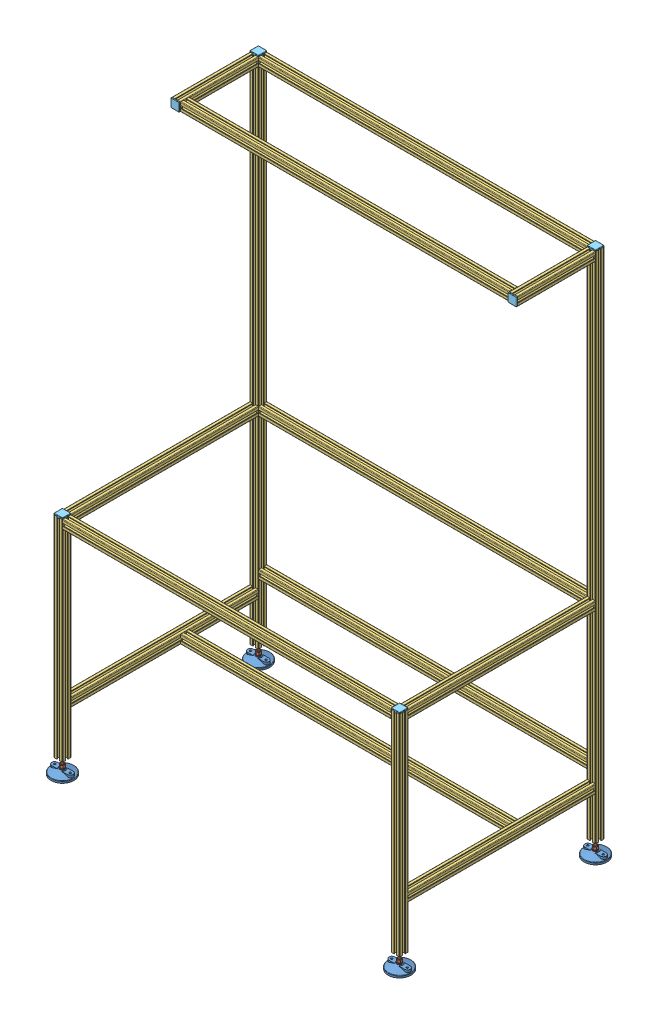
SolidWorks assembly AL-1 Рабочий стол малый, configuration По умолчанию. Lengths in mm.
Overall size (1249 1834.2 759).
56 component instances, 6 part files, 43 mates.
Components (placement in the parent):
- AL-340.010BA.01 Опора D80 с противоскользящей вставкой-8: AL-340.010BA.01 Опора D80 с противоскользящей вставкой [Default] x (0 0 1) z (1 0 0) size (79 18 79)
- AL-1Y12.A42A.01 Шпилька к опоре М8х80-1: AL-1Y12.A42A.01 Шпилька к опоре М8х80 [Default] x (-0.999247 0 -0.038788) z (-0.038788 0 0.999247) size (15 105.5 18.13)
- AL-1-PS-3030.001 Профиль-2: AL-1-PS-3030.001 Профиль [Default] at (0 1765 285) size (30 30 270)
- AL-1-PS-3030.001 Профиль-4: AL-1-PS-3030.001 Профиль [-01] at (0 715 665) size (30 30 650)
- AL-1-PS-3030.001 Профиль-5: AL-1-PS-3030.001 Профиль [-02] at (0 165 665) size (30 30 650)
- AL-1-PS-3030.001 Профиль-3: AL-1-PS-3030.001 Профиль [-03] at (0 0 680) x (1 0 0) z (0 -1 0) size (30 30 730)
- AL-1-PS-3030.001 Профиль-16: AL-1-PS-3030.001 Профиль [-04] at (-1155 1765 270) x (0 0 1) z (-1 0 0) size (30 30 1140)
- AL-1-PS-3030.001 Профиль-11: AL-1-PS-3030.001 Профиль [-04] at (-1155 715 680) x (0 0 1) z (-1 0 0) size (30 30 1140)
- AL-1-PS-3030.001 Профиль-12: AL-1-PS-3030.001 Профиль [-04] at (-1155 715 0) x (0 0 1) z (-1 0 0) size (30 30 1140)
- AL-1-PS-3030.001 Профиль-14: AL-1-PS-3030.001 Профиль [-04] at (-1155 225 0) x (0 0 1) z (-1 0 0) size (30 30 1140)
- AL-1-PS-3030.001 Профиль-15: AL-1-PS-3030.001 Профиль [-04] at (-1155 1765 0) x (0 0 1) z (-1 0 0) size (30 30 1140)
- AL-1-PS-3030.001 Профиль-13: AL-1-PS-3030.001 Профиль [-04] at (-1155 165 270) x (0 0 1) z (-1 0 0) size (30 30 1140)
- AL-1-PS-3030.001 Профиль-1: AL-1-PS-3030.001 Профиль [-05] x (1 0 0) z (0 -1 0) size (30 30 1780)
- AL-340.010BA.01 Опора D80 с противоскользящей вставкой-9: AL-340.010BA.01 Опора D80 с противоскользящей вставкой [Default] at (-1170 0 0) x (0 0 1) z (1 0 0) size (79 18 79)
- AL-340.010BA.01 Опора D80 с противоскользящей вставкой-10: AL-340.010BA.01 Опора D80 с противоскользящей вставкой [Default] at (0 0 680) x (0 0 1) z (1 0 0) size (79 18 79)
- AL-340.010BA.01 Опора D80 с противоскользящей вставкой-11: AL-340.010BA.01 Опора D80 с противоскользящей вставкой [Default] at (-1170 0 680) x (0 0 1) z (1 0 0) size (79 18 79)
- AL-1Y12.A42A.01 Шпилька к опоре М8х80-2: AL-1Y12.A42A.01 Шпилька к опоре М8х80 [Default] at (-1170 0 0) x (-0.999247 0 -0.038788) z (-0.038788 0 0.999247) size (15 105.5 18.13)
- AL-1Y12.A42A.01 Шпилька к опоре М8х80-3: AL-1Y12.A42A.01 Шпилька к опоре М8х80 [Default] at (0 0 680) x (-0.999247 0 -0.038788) z (-0.038788 0 0.999247) size (15 105.5 18.13)
- AL-1Y12.A42A.01 Шпилька к опоре М8х80-4: AL-1Y12.A42A.01 Шпилька к опоре М8х80 [Default] at (-1170 0 680) x (-0.999247 0 -0.038788) z (-0.038788 0 0.999247) size (15 105.5 18.13)
- рабочий стол-1: рабочий стол [ISO 7380 - M8 x 25 - 25S] at (-8.4 1765.0435 0.0024) x (-1 0 0) z (0 0 1) size (29.4 14 14)
- рабочий стол-2: рабочий стол [ISO 7380 - M8 x 25 - 25S] at (0.0215 1765.3277 8.4) x (0 0 1) z (1 0 0) size (29.4 14 14)
- рабочий стол-3: рабочий стол [ISO 7380 - M8 x 25 - 25S] at (0.1511 715.0551 8.3307) x (0 0 1) z (1 0 0) size (29.4 14 14)
- рабочий стол-4: рабочий стол [ISO 7380 - M8 x 25 - 25S] at (-8.2704 714.7709 -0.0669) x (-1 0 0) z (0 0 1) size (29.4 14 14)
- рабочий стол-5: рабочий стол [ISO 7380 - M8 x 25 - 25S] at (-8.3065 224.9725 -0.0017) x (-1 0 0) z (0 0 1) size (29.4 14 14)
- рабочий стол-6: рабочий стол [ISO 7380 - M8 x 25 - 25S] at (0.0945 165.0229 8.3758) x (0 0 1) z (1 0 0) size (29.4 14 14)
- рабочий стол-14: рабочий стол [ISO 7380 - M8 x 25 - 25S] at (-8.2335 1764.9468 270.0007) x (-1 0 0) z (0 0 1) size (29.4 14 14)
- рабочий стол-15: рабочий стол [ISO 7380 - M8 x 25 - 25S] at (-8.2136 165.0415 270.0278) x (-1 0 0) z (0 0 1) size (29.4 14 14)
- рабочий стол-16: рабочий стол [ISO 7380 - M8 x 25 - 25S] at (0.138 164.9906 671.6) x (0 0 -1) z (-1 0 0) size (29.4 14 14)
- рабочий стол-26: рабочий стол [ISO 7380 - M8 x 25 - 25S] at (-8.3088 715.043 680.0577) x (-1 0 0) z (0 0 1) size (29.4 14 14)
- рабочий стол-27: рабочий стол [ISO 7380 - M8 x 25 - 25S] at (0.1187 714.9064 671.6) x (0 0 -1) z (-1 0 0) size (29.4 14 14)
- AL-375.0200A.01 Заглушка торцевая 30х30-34: AL-375.0200A.01 Заглушка торцевая 30х30 [По умолчанию] at (15 1750 289.2) x (-1 0 0) z (0 0 -1) size (30 30 9.2)
- AL-375.0200A.01 Заглушка торцевая 30х30-35: AL-375.0200A.01 Заглушка торцевая 30х30 [По умолчанию] at (15 1784.2 15) x (-1 0 0) z (0 -1 0) size (30 30 9.2)
- AL-375.0200A.01 Заглушка торцевая 30х30-36: AL-375.0200A.01 Заглушка торцевая 30х30 [По умолчанию] at (15 734.2 695) x (-1 0 0) z (0 -1 0) size (30 30 9.2)
- AL-375.0200A.01 Заглушка торцевая 30х30-37: AL-375.0200A.01 Заглушка торцевая 30х30 [По умолчанию] at (-1155 1750 289.2) x (-1 0 0) z (0 0 -1) size (30 30 9.2)
- AL-375.0200A.01 Заглушка торцевая 30х30-38: AL-375.0200A.01 Заглушка торцевая 30х30 [По умолчанию] at (-1155 734.2 695) x (-1 0 0) z (0 -1 0) size (30 30 9.2)
- AL-375.0200A.01 Заглушка торцевая 30х30-39: AL-375.0200A.01 Заглушка торцевая 30х30 [По умолчанию] at (-1155 1784.2 15) x (-1 0 0) z (0 -1 0) size (30 30 9.2)
- AL-1-PS-3030.001 Профиль-22: AL-1-PS-3030.001 Профиль [Default] at (-1170 1765 285) size (30 30 270)
- AL-1-PS-3030.001 Профиль-23: AL-1-PS-3030.001 Профиль [-01] at (-1170 715 15) x (-1 0 0) z (0 0 -1) size (30 30 650)
- AL-1-PS-3030.001 Профиль-24: AL-1-PS-3030.001 Профиль [-02] at (-1170 165 665) size (30 30 650)
- рабочий стол-39: рабочий стол [ISO 7380 - M8 x 25 - 25S] at (-1170.138 164.9906 671.6) x (0 0 -1) z (-1 0 0) size (29.4 14 14)
- рабочий стол-40: рабочий стол [ISO 7380 - M8 x 25 - 25S] at (-1161.7864 165.0415 270.0278) x (1 0 0) z (0 0 -1) size (29.4 14 14)
- рабочий стол-41: рабочий стол [ISO 7380 - M8 x 25 - 25S] at (-1170.0945 165.0229 8.3758) x (0 0 1) z (1 0 0) size (29.4 14 14)
- рабочий стол-42: рабочий стол [ISO 7380 - M8 x 25 - 25S] at (-1161.6935 224.9725 -0.0017) x (1 0 0) z (0 0 -1) size (29.4 14 14)
- рабочий стол-43: рабочий стол [ISO 7380 - M8 x 25 - 25S] at (-1161.6912 715.043 680.0577) x (1 0 0) z (0 0 -1) size (29.4 14 14)
- рабочий стол-44: рабочий стол [ISO 7380 - M8 x 25 - 25S] at (-1170.1187 714.9064 671.6) x (0 0 -1) z (-1 0 0) size (29.4 14 14)
- рабочий стол-45: рабочий стол [ISO 7380 - M8 x 25 - 25S] at (-1170.1511 715.0551 8.3307) x (0 0 1) z (1 0 0) size (29.4 14 14)
- рабочий стол-46: рабочий стол [ISO 7380 - M8 x 25 - 25S] at (-1161.7296 714.7709 -0.0669) x (1 0 0) z (0 0 -1) size (29.4 14 14)
- рабочий стол-47: рабочий стол [ISO 7380 - M8 x 25 - 25S] at (-1161.7665 1764.9468 270.0007) x (1 0 0) z (0 0 -1) size (29.4 14 14)
- рабочий стол-48: рабочий стол [ISO 7380 - M8 x 25 - 25S] at (-1161.6 1765.0435 0.0024) x (1 0 0) z (0 0 -1) size (29.4 14 14)
- рабочий стол-49: рабочий стол [ISO 7380 - M8 x 25 - 25S] at (-1170.0215 1765.3277 8.4) x (0 0 1) z (1 0 0) size (29.4 14 14)
- AL-1-PS-3030.001 Профиль-25: AL-1-PS-3030.001 Профиль [-05] at (-1170 0 0) x (1 0 0) z (0 -1 0) size (30 30 1780)
- AL-1-PS-3030.001 Профиль-26: AL-1-PS-3030.001 Профиль [-03] at (-1170 0 680) x (1 0 0) z (0 -1 0) size (30 30 730)
- hex nut gradec_din-1: hex nut gradec_din [Hexagon Nut ISO 4034 - M8 - N] x (1 0 0) z (0 1 0) size (13 15.01 7.9)
- hex nut gradec_din-2: hex nut gradec_din [Hexagon Nut ISO 4034 - M8 - N] at (-1170 0 0) x (1 0 0) z (0 1 0) size (13 15.01 7.9)
- hex nut gradec_din-3: hex nut gradec_din [Hexagon Nut ISO 4034 - M8 - N] at (0 0 680) x (1 0 0) z (0 1 0) size (13 15.01 7.9)
- hex nut gradec_din-4: hex nut gradec_din [Hexagon Nut ISO 4034 - M8 - N] at (-1170 0 680) x (1 0 0) z (0 1 0) size (13 15.01 7.9)
Mates (geometry in assembly coordinates):
- Совпадение1: coincident aligned: plane of AL-1-PS-3030.001 Профиль-1 through (0 0 0) normal (0 0 1)
- Совпадение2: coincident anti-aligned: plane of AL-1-PS-3030.001 Профиль-1 through (0 0 0) normal (0 -1 0)
- Совпадение3: coincident aligned: plane of AL-1-PS-3030.001 Профиль-1 through (0 0 0) normal (1 0 0)
- Совпадение4: coincident aligned: plane of AL-1-PS-3030.001 Профиль-1 through (15 1780 13) normal (1 0 0); plane of AL-1-PS-3030.001 Профиль-2 through (15 1778 15) normal (1 0 0)
- Совпадение5: coincident anti-aligned: plane of AL-1-PS-3030.001 Профиль-1 through (4.75 1780 15) normal (0 0 1); plane of AL-1-PS-3030.001 Профиль-2 through (-8.05 1752.4 15) normal (0 0 -1)
- Совпадение6: coincident aligned: plane of AL-1-PS-3030.001 Профиль-1 through (-8.05 1780 -12.6) normal (0 1 0); plane of AL-1-PS-3030.001 Профиль-2 through (-4.75 1780 15) normal (0 1 0)
- Совпадение7: coincident aligned: plane of AL-1-PS-3030.001 Профиль-1 through (15 1780 13) normal (1 0 0); plane of AL-1-PS-3030.001 Профиль-3 through (15 730 667) normal (1 0 0)
- Совпадение8: coincident aligned: plane of AL-1-PS-3030.001 Профиль-1 through (-8.05 0 -12.6) normal (0 -1 0); plane of AL-1-PS-3030.001 Профиль-3 through (-8.05 0 667.4) normal (0 -1 0)
- Совпадение9: coincident aligned: plane of AL-1-PS-3030.001 Профиль-3 through (-8.05 730 667.4) normal (0 1 0); plane of AL-1-PS-3030.001 Профиль-4 through (4.75 730 15) normal (0 1 0)
- Совпадение10: coincident aligned: plane of AL-1-PS-3030.001 Профиль-3 through (15 730 693) normal (1 0 0); plane of AL-1-PS-3030.001 Профиль-4 through (15 728 15) normal (1 0 0)
- Совпадение11: coincident anti-aligned: plane of AL-1-PS-3030.001 Профиль-3 through (4.75 730 665) normal (0 0 -1); plane of AL-1-PS-3030.001 Профиль-4 through (-8.05 702.4 665) normal (0 0 1)
- Совпадение12: coincident anti-aligned: plane of AL-1-PS-3030.001 Профиль-1 through (4.75 1780 15) normal (0 0 1); plane of AL-1-PS-3030.001 Профиль-4 through (-8.05 702.4 15) normal (0 0 -1)
- Совпадение13: coincident aligned: plane of AL-1-PS-3030.001 Профиль-4 through (15 728 15) normal (1 0 0); plane of AL-1-PS-3030.001 Профиль-5 through (15 178 15) normal (1 0 0)
- Расстояние1: distance = 150 mm aligned: plane of AL-1-PS-3030.001 Профиль-5 through (4.75 150 15) normal (0 -1 0); plane of AL-1-PS-3030.001 Профиль-3 through (-8.05 0 667.4) normal (0 -1 0)
- Совпадение15: coincident anti-aligned: plane of AL-1-PS-3030.001 Профиль-3 through (4.75 730 665) normal (0 0 -1); plane of AL-1-PS-3030.001 Профиль-5 through (-8.05 152.4 665) normal (0 0 1)
- Совпадение16: coincident aligned: plane of AL-1-PS-3030.001 Профиль-3 through (-8.05 730 667.4) normal (0 1 0); plane of AL-1-PS-3030.001 Профиль-11 through (-15 730 684.75) normal (0 1 0)
- Совпадение17: coincident aligned: plane of AL-1-PS-3030.001 Профиль-3 through (-4.75 730 695) normal (0 0 1); plane of AL-1-PS-3030.001 Профиль-11 through (-15 728 695) normal (0 0 1)
- Совпадение18: coincident anti-aligned: plane of AL-1-PS-3030.001 Профиль-3 through (-15 730 693) normal (-1 0 0); plane of AL-1-PS-3030.001 Профиль-11 through (-15 702.4 671.95) normal (1 0 0)
- Совпадение19: coincident aligned: plane of AL-1-PS-3030.001 Профиль-11 through (-15 730 684.75) normal (0 1 0); plane of AL-1-PS-3030.001 Профиль-12 through (-15 730 4.75) normal (0 1 0)
- Совпадение21: coincident aligned: plane of AL-1-PS-3030.001 Профиль-11 through (-1155 702.4 671.95) normal (-1 0 0); plane of AL-1-PS-3030.001 Профиль-12 through (-1155 702.4 -8.05) normal (-1 0 0)
- Совпадение22: coincident aligned: plane of AL-1-PS-3030.001 Профиль-5 through (4.75 180 15) normal (0 1 0); plane of AL-1-PS-3030.001 Профиль-13 through (-15 180 274.75) normal (0 1 0)
- Совпадение23: coincident anti-aligned: plane of AL-1-PS-3030.001 Профиль-5 through (-15 152 15) normal (-1 0 0); plane of AL-1-PS-3030.001 Профиль-13 through (-15 152.4 261.95) normal (1 0 0)
- Расстояние2: distance = 240 mm anti-aligned: plane of AL-1-PS-3030.001 Профиль-13 through (-15 178 255) normal (0 0 -1); plane of AL-1-PS-3030.001 Профиль-1 through (-4.75 1780 15) normal (0 0 1)
- Совпадение25: coincident aligned: plane of AL-1-PS-3030.001 Профиль-2 through (-8.05 1752.4 285) normal (0 0 1); plane of AL-1-PS-3030.001 Профиль-16 through (-15 1778 285) normal (0 0 1)
- Совпадение26: coincident anti-aligned: plane of AL-1-PS-3030.001 Профиль-2 through (-15 1778 15) normal (-1 0 0); plane of AL-1-PS-3030.001 Профиль-16 through (-15 1752.4 261.95) normal (1 0 0)
- Совпадение27: coincident aligned: plane of AL-1-PS-3030.001 Профиль-2 through (-4.75 1780 15) normal (0 1 0); plane of AL-1-PS-3030.001 Профиль-16 through (-15 1780 274.75) normal (0 1 0)
- Концентричный2: concentric anti-aligned: cylinder of AL-1Y12.A42A.01 Шпилька к опоре М8х80-1 through (0 -18 0) axis (0 1 0) radius 4; cylinder of AL-340.010BA.01 Опора D80 с противоскользящей вставкой-8 through (0 0 0) axis (0 -1 0) radius 39.5
- Концентричный272: concentric anti-aligned: cylinder of AL-1-PS-3030.001 Профиль-1 through (0 1780 0) axis (0 -1 0) radius 3.65; cylinder of AL-1Y12.A42A.01 Шпилька к опоре М8х80-1 through (0 -18 0) axis (0 1 0) radius 4
- Совпадение564: coincident anti-aligned: plane of AL-1-PS-3030.001 Профиль-1 through (-12.8 1780 8.05) normal (1 0 0); plane of socket button head screw_iso-1 through (-12.8 1761.0435 0.0024) normal (-1 0 0)
- Совпадение565: coincident anti-aligned: plane of AL-1-PS-3030.001 Профиль-1 through (4.65 1780 12.8) normal (0 0 -1); plane of socket button head screw_iso-2 through (0.0215 1761.3277 12.8) normal (0 0 1)
- Совпадение567: coincident anti-aligned: plane of AL-1-PS-3030.001 Профиль-3 through (-4.65 730 667.2) normal (0 0 1); plane of socket button head screw_iso-16 through (0.138 160.9906 667.2) normal (0 0 -1)
- Совпадение568: coincident anti-aligned: plane of AL-1-PS-3030.001 Профиль-3 through (-4.65 730 667.2) normal (0 0 1); plane of socket button head screw_iso-27 through (0.1187 710.9064 667.2) normal (0 0 -1)
- Совпадение571: coincident anti-aligned: plane of AL-1-PS-3030.001 Профиль-2 through (-8.05 1752.4 285) normal (0 0 1); plane of AL-375.0200A.01 Заглушка торцевая 30х30-34 through (-3.6986 1780 285) normal (0 0 -1)
- Совпадение572: coincident aligned: plane of AL-1-PS-3030.001 Профиль-2 through (15 1778 15) normal (1 0 0); plane of AL-375.0200A.01 Заглушка торцевая 30х30-34 through (15 1750 289.2) normal (1 0 0)
- Совпадение573: coincident aligned: plane of AL-1-PS-3030.001 Профиль-2 through (4.75 1780 15) normal (0 1 0); plane of AL-375.0200A.01 Заглушка торцевая 30х30-34 through (15 1780 289.2) normal (0 1 0)
- Совпадение574: coincident anti-aligned: plane of AL-1-PS-3030.001 Профиль-1 through (-8.05 1780 -12.6) normal (0 1 0); plane of AL-375.0200A.01 Заглушка торцевая 30х30-35 through (-3.6986 1780 -15) normal (0 -1 0)
- Совпадение575: coincident aligned: plane of AL-1-PS-3030.001 Профиль-1 through (4.75 1780 -15) normal (0 0 -1); plane of AL-375.0200A.01 Заглушка торцевая 30х30-35 through (15 1784.2 -15) normal (0 0 -1)
- Совпадение576: coincident aligned: plane of AL-1-PS-3030.001 Профиль-1 through (15 1780 -13) normal (1 0 0); plane of AL-375.0200A.01 Заглушка торцевая 30х30-35 through (15 1784.2 15) normal (1 0 0)
- Совпадение577: coincident anti-aligned: plane of AL-1-PS-3030.001 Профиль-3 through (-8.05 730 667.4) normal (0 1 0); plane of AL-375.0200A.01 Заглушка торцевая 30х30-36 through (-3.6986 730 665) normal (0 -1 0)
- Совпадение578: coincident aligned: plane of AL-1-PS-3030.001 Профиль-3 through (15 730 667) normal (1 0 0); plane of AL-375.0200A.01 Заглушка торцевая 30х30-36 through (15 734.2 695) normal (1 0 0)
- Совпадение579: coincident aligned: plane of AL-1-PS-3030.001 Профиль-3 through (4.75 730 695) normal (0 0 1); plane of AL-375.0200A.01 Заглушка торцевая 30х30-36 through (15 734.2 695) normal (0 0 1)
- Концентричный274: concentric aligned: cylinder of AL-1Y12.A42A.01 Шпилька к опоре М8х80-1 through (0 -18 0) axis (0 1 0) radius 4; cylinder of hex nut gradec_din-1 through (0 -7.9 0) axis (0 1 0) radius 3.4
- Совпадение580: coincident anti-aligned: plane of AL-1-PS-3030.001 Профиль-1 through (-8.05 0 -12.6) normal (0 -1 0); plane of hex nut gradec_din-1 through (-13 0 0) normal (0 1 0)
